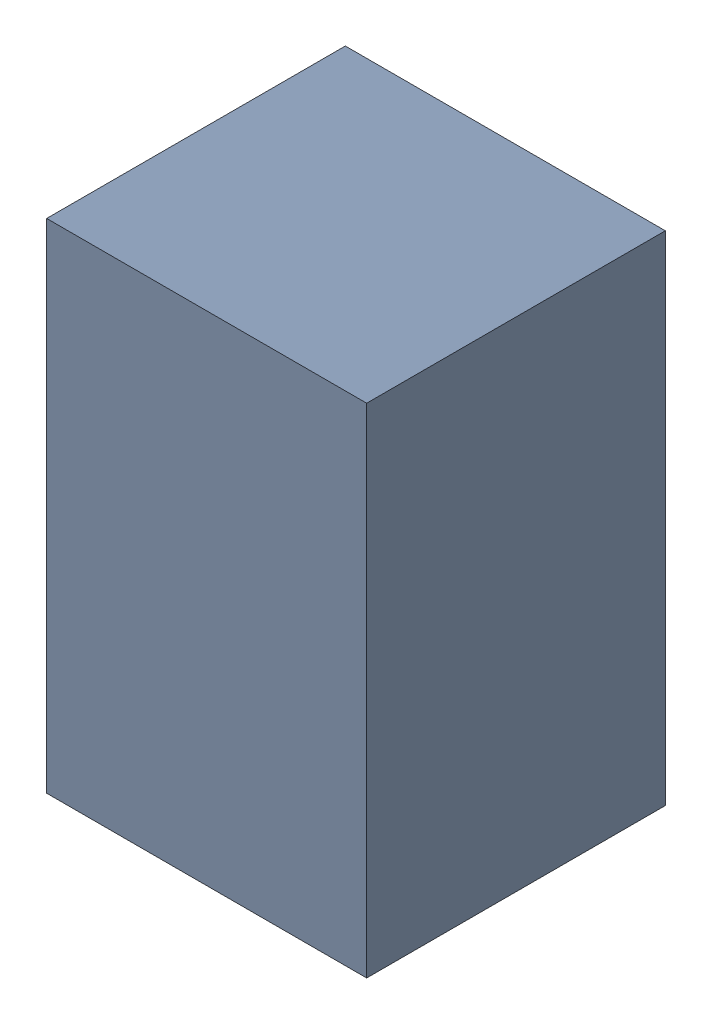
SolidWorks assembly C8_1, configuration Default. Lengths in mm.
Overall size (1.35 2.1 1.26).
2 component instances, 1 part files, 0 mates.
Components (placement in the parent):
- 407985696_1-1: 407985696_1 [Default] at (16.891 12.623 0.0127) size (1.35 2.1 1.26)
  - Extruded_6-1: Extruded_6 [Default] at origin size (1.35 2.1 1.26)
